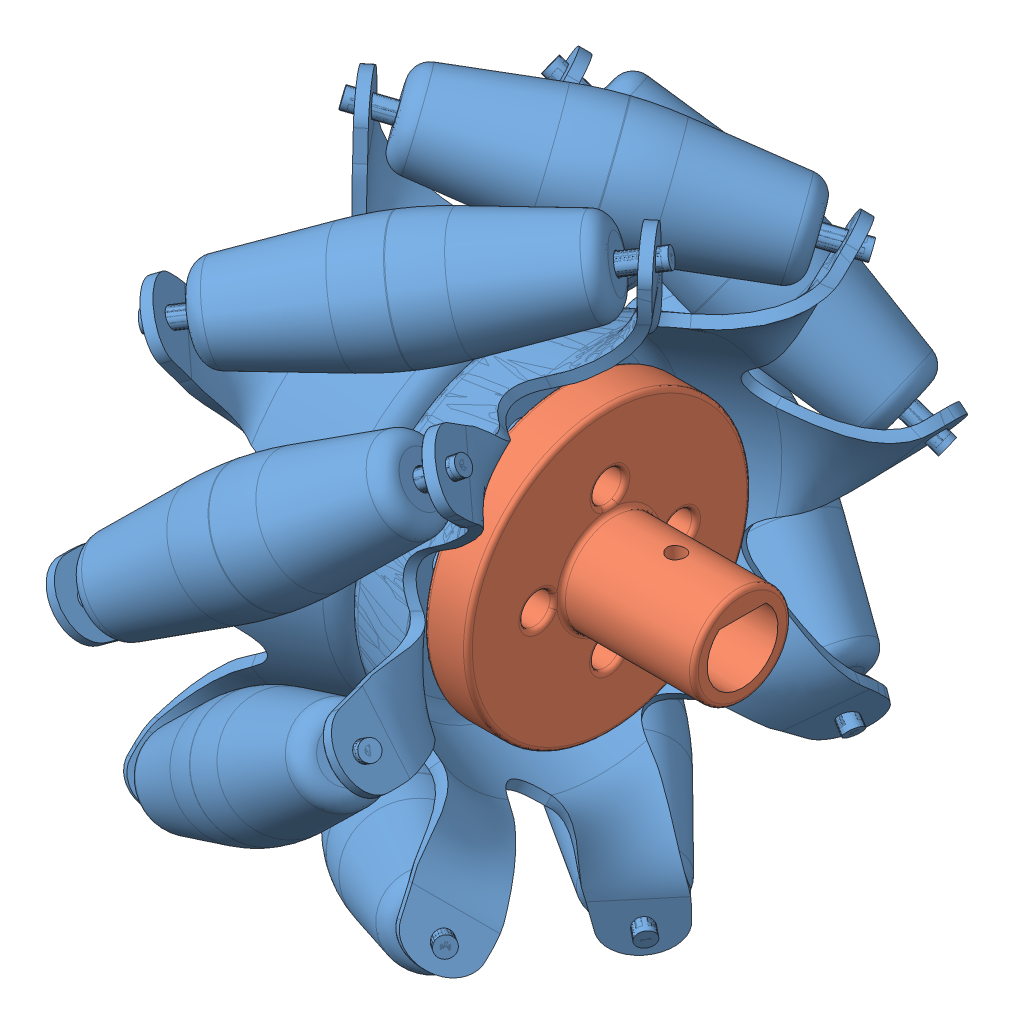
SolidWorks assembly Macenum wheel couplers, configuration Default. Lengths in mm.
Overall size (45.29 71.41 71.41).
3 component instances, 3 part files, 3 mates.
Components (placement in the parent):
- Macenum Wheel-1: Macenum Wheel [Default] at (-52.4678 8.4309 21.9588) size (37.4 71.41 71.41)
- Coupler front-1: Coupler front [Default] at (-45.8799 8.4309 21.9588) x (0 -0.004083 -0.999992) z (0 -0.999992 0.004083) size (32 25 32)
- Coupler back-1: Coupler back [Default] at (-55.2277 8.4309 21.9588) x (0 0.004083 0.999992) z (0 -0.999992 0.004083) size (32 5 32)
Mates (geometry in assembly coordinates):
- Concentric1: concentric: cylinder of Macenum Wheel-1 through (-71.1672 8.4309 21.9588) axis (1 0 0) radius 4.2356; cylinder of Coupler front-1 through (-40.8799 8.4309 21.9588) axis (-1 0 0) radius 16
- Concentric2: concentric: cylinder of Macenum Wheel-1 through (-71.1672 8.4309 21.9588) axis (1 0 0) radius 4.2356; cylinder of Coupler back-1 through (-57.2277 8.4309 21.9588) axis (1 0 0) radius 16
- Concentric3: concentric: cylinder of Coupler front-1 through (-45.8799 16.4308 21.9261) axis (1 0 0) radius 1.75; cylinder of Coupler back-1 through (-55.2277 20.4308 21.9098) axis (-1 0 0) radius 2.25
